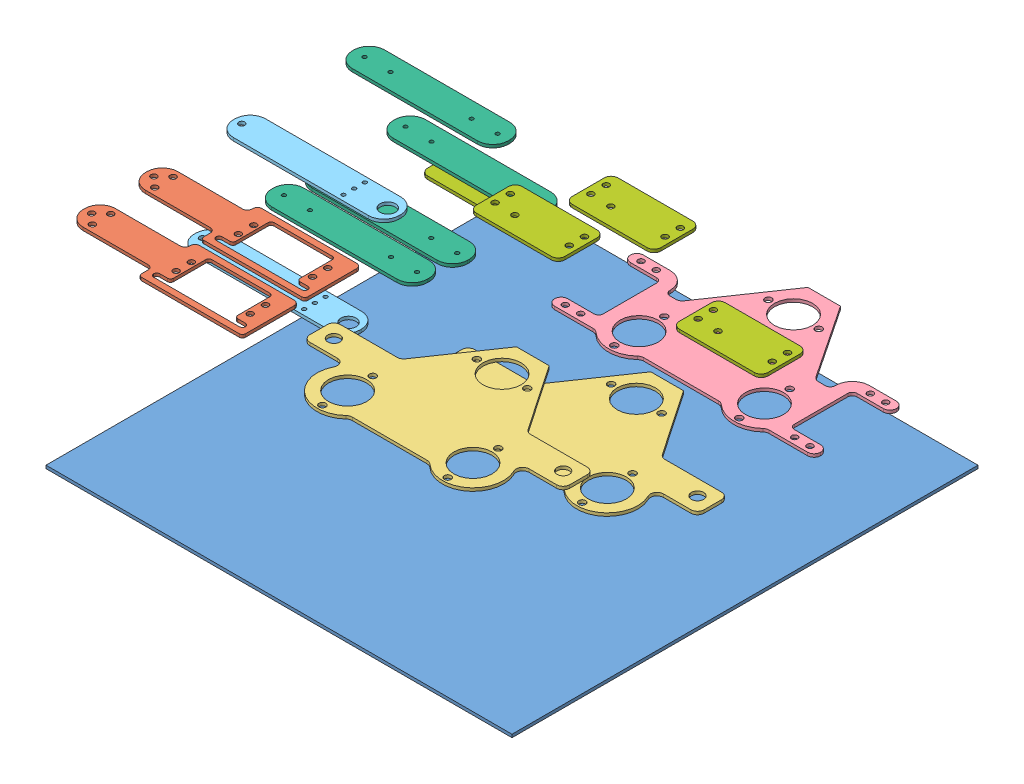
SolidWorks assembly waterjet_setup, configuration Default. Lengths in mm.
Overall size (304.8 140.11 304.8).
16 component instances, 7 part files, 12 mates.
Components (placement in the parent):
- stock-1: stock [Default] at (141.8197 0 235.433) size (304.8 2 304.8)
- leg_lower_1-1: leg_lower_1 [Default] at (29.7651 135.1097 324.0891) size (123.5 2 37)
- hip_frame_2-1: hip_frame_2 [Default] at (194.89 52 242.1638) x (1 0 0) z (0 -1 0) size (170 100 2)
- leg_lower_1-2: leg_lower_1 [Default] at (30.3325 135.1097 365.4189) size (123.5 2 37)
- hip_frame_1-1: hip_frame_1 [Default] at (198.4612 52 142.9305) x (1 0 0) z (0 -1 0) size (174 100 2)
- leg_lower_2-1: leg_lower_2 [Default] at (30.5962 85.1097 293.1407) size (108.5 2 21.12)
- leg_upper_1-1: leg_upper_1 [Default] at (43.8424 85.1097 163.6187) size (102 2 21.12)
- leg_upper_1-2: leg_upper_1 [Default] at (41.8994 84.1097 241.1978) size (102 2 21.12)
- leg_upper_1-3: leg_upper_1 [Default] at (43.3195 83.1097 216.3247) size (102 2 21.12)
- leg_upper_1-4: leg_upper_1 [Default] at (43.9756 138.1097 190.5266) size (102 2 21.12)
- leg_lower_2-2: leg_lower_2 [Default] at (31.6309 138.1097 268.5028) size (108.5 2 21.12)
- hip_1-1: hip_1 [Default] at (88.2556 52 103.0046) x (0 0 1) z (0 -1 0) size (30 58 2)
- hip_1-2: hip_1 [Default] at (24.8944 52 134.2291) x (0 0 1) z (0 -1 0) size (30 58 2)
- hip_1-3: hip_1 [Default] at (262.0192 120 206.6604) x (0 0 1) z (0 -1 0) size (30 58 2)
- hip_1-4: hip_1 [Default] at (129.8405 120 207.2996) x (0 0 1) z (0 -1 0) size (30 58 2)
- hip_frame_2-2: hip_frame_2 [Default] at (204.795 120 339.9193) x (1 0 0) z (0 -1 0) size (170 100 2)
Mates (geometry in assembly coordinates):
- Distance2: distance = 50 mm anti-aligned: plane of hip_frame_1-1 through (198.4612 50 142.9305) normal (0 -1 0)
- Distance1: distance = 50 mm anti-aligned: plane of hip_frame_2-1 through (194.89 50 242.1638) normal (0 -1 0)
- Coincident3: coincident aligned: plane of stock-1 through (141.8197 0 235.433) normal (0 1 0)
- Distance5: distance = 50 mm anti-aligned: plane of hip_1-2 through (24.8944 50 134.2291) normal (0 -1 0)
- Distance6: distance = 50 mm anti-aligned: plane of hip_1-1 through (88.2556 50 103.0046) normal (0 -1 0)
- Parallel2: parallel anti-aligned: plane of hip_1-2 through (-4.1056 50 119.2291) normal (-1 0 0)
- Parallel3: parallel anti-aligned: plane of hip_1-1 through (59.2556 50 88.0046) normal (-1 0 0)
- Distance7: distance = 120 mm anti-aligned: plane of hip_1-4 through (129.8405 120 207.2996) normal (0 -1 0)
- Distance8: distance = 120 mm anti-aligned: plane of hip_1-3 through (262.0192 120 206.6604) normal (0 -1 0)
- Parallel4: parallel anti-aligned: plane of hip_1-3 through (262.0192 120 206.6604) normal (-1 0 0)
- Parallel5: parallel anti-aligned: plane of hip_1-4 through (129.8405 120 207.2996) normal (-1 0 0)
- Distance10: distance = 120 mm anti-aligned: plane of hip_frame_2-2 through (204.795 120 339.9193) normal (0 -1 0)
